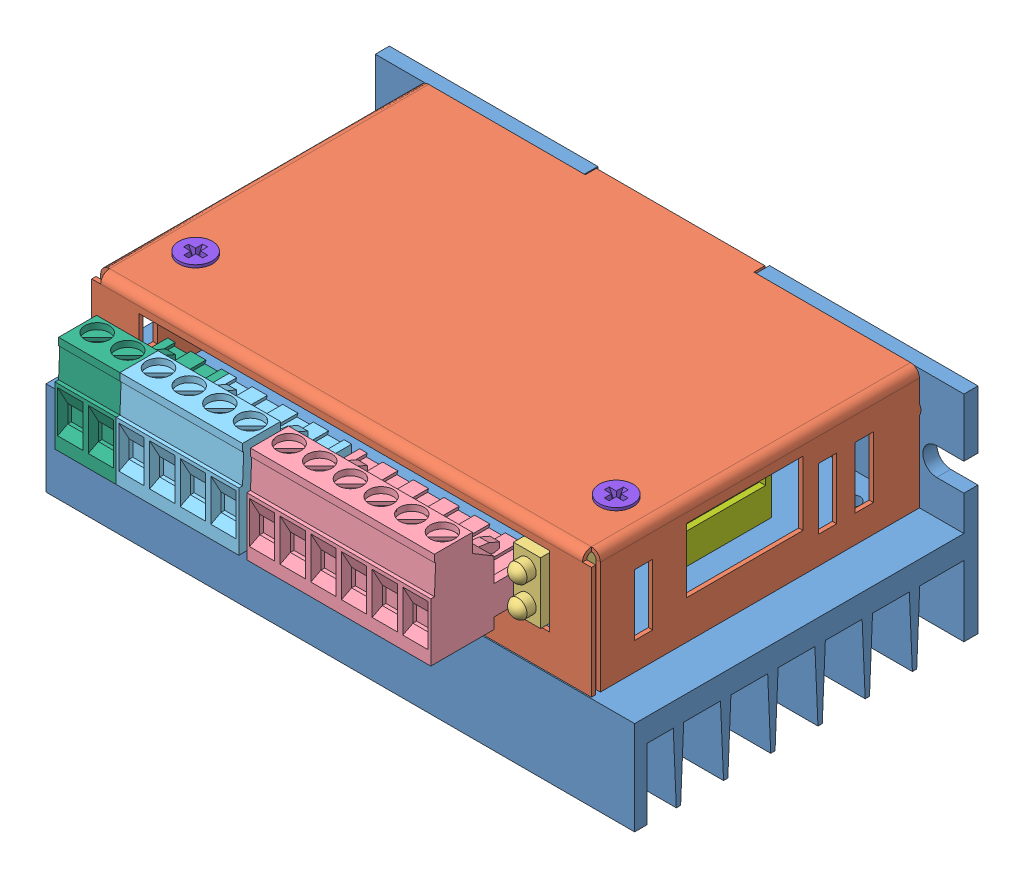
SolidWorks assembly SMAKN TB6600 STEPPER MOTOR DRIVER, configuration Default. Lengths in mm.
Overall size (96 36.6 70.3).
9 component instances, 8 part files, 21 mates.
Components (placement in the parent):
- HEATSINK STYLE MOUNTING PLATE, SMAKN TB6600 STEPPER MOTOR DRIVER-1: HEATSINK STYLE MOUNTING PLATE, SMAKN TB6600 STEPPER MOTOR DRIVER [Default] at origin size (96 35 56)
- SHEET METAL ENCLOSURE, SMAKN TB6600 STEPPER MOTOR DRIVER-1: SHEET METAL ENCLOSURE, SMAKN TB6600 STEPPER MOTOR DRIVER [Default] at (0 23.6 0.32) size (81.5 19.8 55.8)
- LED BODY, SMAKN TB6600 STEPPER MOTOR DRIVER-1: LED BODY, SMAKN TB6600 STEPPER MOTOR DRIVER [Default] at (31.25 15.35 28.8) size (4.4 10 12.5)
- EUROSTYLE TERMINAL BLOCK 6 POS 5.0 MM RA PLUG, SMAKN TB6600 STEPPER MOTOR DRIVER-1: EUROSTYLE TERMINAL BLOCK 6 POS 5.0 MM RA PLUG, SMAKN TB6600 STEPPER MOTOR DRIVER [Default] at (14.05 13.1 23.9) x (-1 0 0) z (0 0 -1) size (30 15.5 18.4)
- EUROSTYLE TERMINAL BLOCK 4 POS 5.0 MM RA PLUG, SMAKN TB6600 STEPPER MOTOR DRIVER-1: EUROSTYLE TERMINAL BLOCK 4 POS 5.0 MM RA PLUG, SMAKN TB6600 STEPPER MOTOR DRIVER [Default] at (-12.25 13.1 23.9) x (-1 0 0) z (0 0 -1) size (20 15.5 18.4)
- EUROSTYLE TERMINAL BLOCK 2 POS 5.0 MM RA PLUG, SMAKN TB6600 STEPPER MOTOR DRIVER-1: EUROSTYLE TERMINAL BLOCK 2 POS 5.0 MM RA PLUG, SMAKN TB6600 STEPPER MOTOR DRIVER [Default] at (-27.25 13.1 23.9) x (-1 0 0) z (0 0 -1) size (10 15.5 18.4)
- DIP SWITCH, SMAKN TB6600 STEPPER MOTOR DRIVER-1: DIP SWITCH, SMAKN TB6600 STEPPER MOTOR DRIVER [Default] at (-35.55 -6.1 25.1) size (10.9 9 16)
- flat head screw_am-1: flat head screw_am [B18.6.7M - M3 x 0.5 x 6 Type I Cross Recessed FHMS --6N] at (-34.3 24.05 17.3) x (0 -1 0) z (0.999962 0 -0.008775) size (6 5.5 5.5)
- flat head screw_am-2: flat head screw_am [B18.6.7M - M3 x 0.5 x 6 Type I Cross Recessed FHMS --6N] at (34.3 24.05 17.3) x (0 -1 0) z (0.999962 0 0.008775) size (6 5.5 5.5)
Mates (geometry in assembly coordinates):
- Coincident1: coordinate: point of HEATSINK STYLE MOUNTING PLATE, SMAKN TB6600 STEPPER MOTOR DRIVER-1
- Coincident2: coincident aligned: plane of SHEET METAL ENCLOSURE, SMAKN TB6600 STEPPER MOTOR DRIVER-1 through (0 23.6 0.32) normal (1 0 0)
- Coincident3: coincident anti-aligned: plane of HEATSINK STYLE MOUNTING PLATE, SMAKN TB6600 STEPPER MOTOR DRIVER-1 through (0 3.8 0) normal (0 1 0); plane of SHEET METAL ENCLOSURE, SMAKN TB6600 STEPPER MOTOR DRIVER-1 through (40.75 3.8 26.34) normal (0 -1 0)
- Coincident4: coincident anti-aligned: plane of HEATSINK STYLE MOUNTING PLATE, SMAKN TB6600 STEPPER MOTOR DRIVER-1 through (0 0 -25.7) normal (0 0 1); plane of SHEET METAL ENCLOSURE, SMAKN TB6600 STEPPER MOTOR DRIVER-1 through (-39.29 22.9 -25.7) normal (0 0 -1)
- Width1: width aligned: plane of SHEET METAL ENCLOSURE, SMAKN TB6600 STEPPER MOTOR DRIVER-1 through (-33.05 9.6 -28.001) normal (0 1 0); plane of LED BODY, SMAKN TB6600 STEPPER MOTOR DRIVER-1 through (-33.05 21.1 -28.001) normal (0 -1 0); plane of SHEET METAL ENCLOSURE, SMAKN TB6600 STEPPER MOTOR DRIVER-1 through (29.05 20.35 18.8) normal (0 1 0); plane of LED BODY, SMAKN TB6600 STEPPER MOTOR DRIVER-1 through (29.05 10.35 18.8) normal (0 -1 0)
- Distance1: distance = 1 mm aligned: plane of SHEET METAL ENCLOSURE, SMAKN TB6600 STEPPER MOTOR DRIVER-1 through (0 23.6 27.8) normal (0 0 1); plane of LED BODY, SMAKN TB6600 STEPPER MOTOR DRIVER-1 through (31.25 15.35 28.8) normal (0 0 1)
- Distance2: distance = 0.5 mm anti-aligned: plane of SHEET METAL ENCLOSURE, SMAKN TB6600 STEPPER MOTOR DRIVER-1 through (33.95 9.6 -28.001) normal (-1 0 0); plane of LED BODY, SMAKN TB6600 STEPPER MOTOR DRIVER-1 through (33.45 20.35 18.8) normal (1 0 0)
- Coincident5: coincident anti-aligned: plane of SHEET METAL ENCLOSURE, SMAKN TB6600 STEPPER MOTOR DRIVER-1 through (-33.05 9.6 -28.001) normal (0 1 0); plane of EUROSTYLE TERMINAL BLOCK 6 POS 5.0 MM RA PLUG, SMAKN TB6600 STEPPER MOTOR DRIVER-1 through (29.05 9.6 23.9) normal (0 -1 0)
- Distance3: distance = 14.5 mm aligned: plane of SHEET METAL ENCLOSURE, SMAKN TB6600 STEPPER MOTOR DRIVER-1 through (0 23.6 27.8) normal (0 0 1); plane of EUROSTYLE TERMINAL BLOCK 6 POS 5.0 MM RA PLUG, SMAKN TB6600 STEPPER MOTOR DRIVER-1 through (29.05 9.6 42.3) normal (0 0 1)
- Coincident6: coincident anti-aligned: plane of LED BODY, SMAKN TB6600 STEPPER MOTOR DRIVER-1 through (29.05 20.35 18.8) normal (-1 0 0); plane of EUROSTYLE TERMINAL BLOCK 6 POS 5.0 MM RA PLUG, SMAKN TB6600 STEPPER MOTOR DRIVER-1 through (29.05 13.1 23.9) normal (1 0 0)
- Coincident7: coincident aligned: plane of EUROSTYLE TERMINAL BLOCK 6 POS 5.0 MM RA PLUG, SMAKN TB6600 STEPPER MOTOR DRIVER-1 through (29.05 9.6 42.3) normal (0 0 1); plane of EUROSTYLE TERMINAL BLOCK 4 POS 5.0 MM RA PLUG, SMAKN TB6600 STEPPER MOTOR DRIVER-1 through (-2.25 9.6 42.3) normal (0 0 1)
- Coincident8: coincident aligned: plane of EUROSTYLE TERMINAL BLOCK 6 POS 5.0 MM RA PLUG, SMAKN TB6600 STEPPER MOTOR DRIVER-1 through (29.05 9.6 23.9) normal (0 -1 0); plane of EUROSTYLE TERMINAL BLOCK 4 POS 5.0 MM RA PLUG, SMAKN TB6600 STEPPER MOTOR DRIVER-1 through (-2.25 9.6 23.9) normal (0 -1 0)
- Coincident9: coincident aligned: plane of EUROSTYLE TERMINAL BLOCK 4 POS 5.0 MM RA PLUG, SMAKN TB6600 STEPPER MOTOR DRIVER-1 through (-2.25 9.6 42.3) normal (0 0 1); plane of EUROSTYLE TERMINAL BLOCK 2 POS 5.0 MM RA PLUG, SMAKN TB6600 STEPPER MOTOR DRIVER-1 through (-22.25 9.6 42.3) normal (0 0 1)
- Coincident10: coincident anti-aligned: plane of EUROSTYLE TERMINAL BLOCK 4 POS 5.0 MM RA PLUG, SMAKN TB6600 STEPPER MOTOR DRIVER-1 through (-22.25 13.1 23.9) normal (-1 0 0); plane of EUROSTYLE TERMINAL BLOCK 2 POS 5.0 MM RA PLUG, SMAKN TB6600 STEPPER MOTOR DRIVER-1 through (-22.25 13.1 23.9) normal (1 0 0)
- Coincident11: coincident aligned: plane of EUROSTYLE TERMINAL BLOCK 4 POS 5.0 MM RA PLUG, SMAKN TB6600 STEPPER MOTOR DRIVER-1 through (-2.25 9.6 23.9) normal (0 -1 0); plane of EUROSTYLE TERMINAL BLOCK 2 POS 5.0 MM RA PLUG, SMAKN TB6600 STEPPER MOTOR DRIVER-1 through (-22.25 9.6 23.9) normal (0 -1 0)
- Distance4: distance = 0.8 mm anti-aligned: plane of SHEET METAL ENCLOSURE, SMAKN TB6600 STEPPER MOTOR DRIVER-1 through (-33.05 9.6 -28.001) normal (1 0 0); plane of EUROSTYLE TERMINAL BLOCK 2 POS 5.0 MM RA PLUG, SMAKN TB6600 STEPPER MOTOR DRIVER-1 through (-32.25 13.1 23.9) normal (-1 0 0)
- Distance5: distance = 1.7 mm anti-aligned: plane of DIP SWITCH, SMAKN TB6600 STEPPER MOTOR DRIVER-1 through (26.95 10.7 10.6) normal (0 0 1); plane of SHEET METAL ENCLOSURE, SMAKN TB6600 STEPPER MOTOR DRIVER-1 through (-40.751 20.6 12.3) normal (0 0 -1)
- Distance6: distance = 0.6 mm anti-aligned: plane of SHEET METAL ENCLOSURE, SMAKN TB6600 STEPPER MOTOR DRIVER-1 through (-40.751 10.1 12.3) normal (0 1 0); plane of DIP SWITCH, SMAKN TB6600 STEPPER MOTOR DRIVER-1 through (26.95 10.7 -5.4) normal (0 -1 0)
- Distance7: distance = 3.8 mm aligned: plane of SHEET METAL ENCLOSURE, SMAKN TB6600 STEPPER MOTOR DRIVER-1 through (40.75 23.6 0.32) normal (1 0 0); plane of DIP SWITCH, SMAKN TB6600 STEPPER MOTOR DRIVER-1 through (36.95 10.7 -5.4) normal (1 0 0)
- Concentric1: concentric aligned: cylinder of SHEET METAL ENCLOSURE, SMAKN TB6600 STEPPER MOTOR DRIVER-1 through (-34.3 23.6 17.3) axis (0 1 0) radius 1.7; cylinder of flat head screw_am-1 through (-34.3 30.4 17.3) axis (0 1 0) radius 1.5
- Coincident12: coincident aligned: circle of SHEET METAL ENCLOSURE, SMAKN TB6600 STEPPER MOTOR DRIVER-1; circle of flat head screw_am-1
